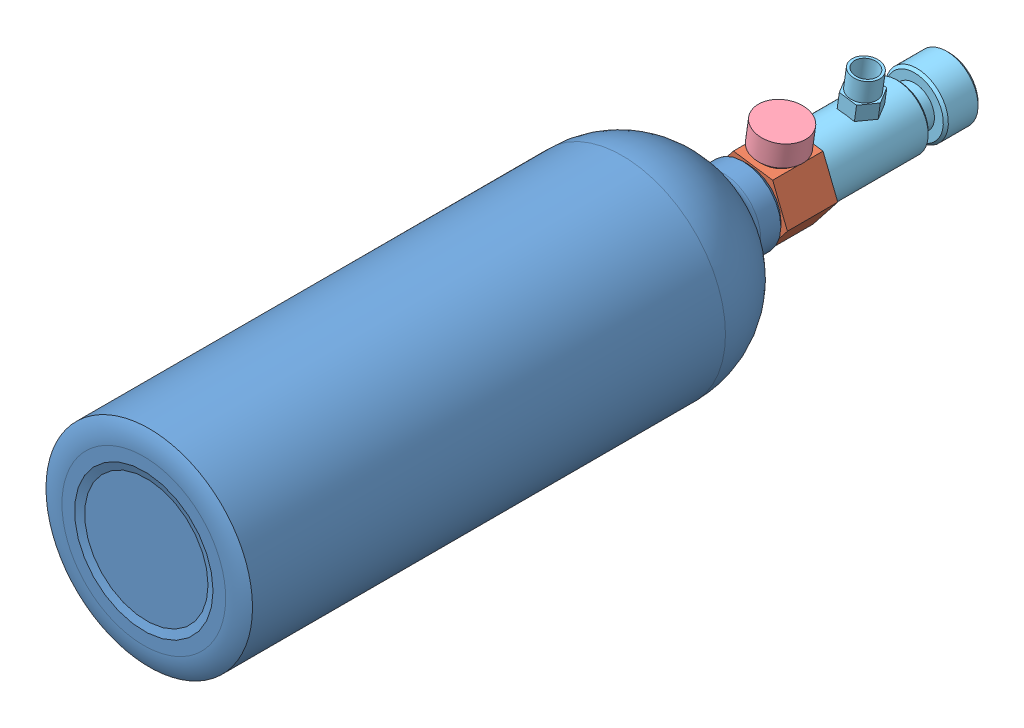
SolidWorks assembly Assem3, configuration Default. Lengths in mm.
Overall size (82.89 82 328.98).
5 component instances, 5 part files, 9 mates.
Components (placement in the parent):
- SE_01_1_2001-1: SE_01_1_2001 [Default] at origin size (82 82 240)
- SE_01_1_2002-1: SE_01_1_2002 [Default] at (0 0 -186.7314) x (-0.989874 0.141952 0) z (0 0 -1) size (31.5 40.28 51)
- SE_01_1_2003-1: SE_01_1_2003 [Default] at (0 0 -220.7314) x (-0.998845 0.048051 0) z (-0.048051 -0.998845 0) size (18.5 2 18.5)
- SE_01_1_2004-1: SE_01_1_2004 [Default] at (3.4977 24.3904 -196.7314) x (0.189946 -0.027239 -0.981417) z (-0.141952 -0.989874 0) size (19 19 9)
- SE_01_1_2005-1: SE_01_1_2005 [Default] at (0 0 -251.5061) x (0.989874 -0.141952 0) z (0.141952 0.989874 0) size (70.53 79.28 39)
Mates (geometry in assembly coordinates):
- Concentric1: concentric anti-aligned: cylinder of SE_01_1_2001-1 through (0 0 52.2686) axis (0 0 1) radius 8; cylinder of SE_01_1_2002-1 through (0 0 -171.7314) axis (0 0 -1) radius 8
- Coincident1: coincident anti-aligned: plane of SE_01_1_2001-1 through (-8 0 -186.7314) normal (0 0 -1); plane of SE_01_1_2002-1 through (0 0 -186.7314) normal (0 0 1)
- Concentric2: concentric anti-aligned: cylinder of SE_01_1_2002-1 through (3.2138 22.4106 -196.7314) axis (-0.141952 -0.989874 0) radius 7.5; cylinder of SE_01_1_2004-1 through (2.2201 15.4815 -196.7314) axis (0.141952 0.989874 0) radius 9.5
- Coincident2: coincident anti-aligned: plane of SE_01_1_2002-1 through (3.2138 22.4106 -196.7314) normal (0.141952 0.989874 0); plane of SE_01_1_2004-1 through (3.2138 22.4106 -196.7314) normal (-0.141952 -0.989874 0)
- Tangent1: tangent: plane of SE_01_1_2002-1 through (8.6614 -1.2421 -221.7314) normal (0 0 1); torus of SE_01_1_2003-1
- Tangent2: tangent: cylinder of SE_01_1_2002-1 through (0 0 -227.3886) axis (0 0 -1) radius 7.25; torus of SE_01_1_2003-1
- Concentric3: concentric aligned: cylinder of SE_01_1_2002-1 through (0 0 -216.7314) axis (0 0 1) radius 10; cylinder of SE_01_1_2005-1 through (0 0 -206.7314) axis (0 0 1) radius 9
- Coincident3: coincident anti-aligned: plane of SE_01_1_2002-1 through (0 0 -206.7314) normal (0 0 -1); plane of SE_01_1_2005-1 through (0 0 -206.7314) normal (0 0 1)
- Parallel1: parallel aligned: plane of SE_01_1_2004-1 through (3.4977 24.3904 -196.7314) normal (0.141952 0.989874 0); plane of SE_01_1_2005-1 through (3.7617 26.2316 -229.7314) normal (0.141952 0.989874 0)
